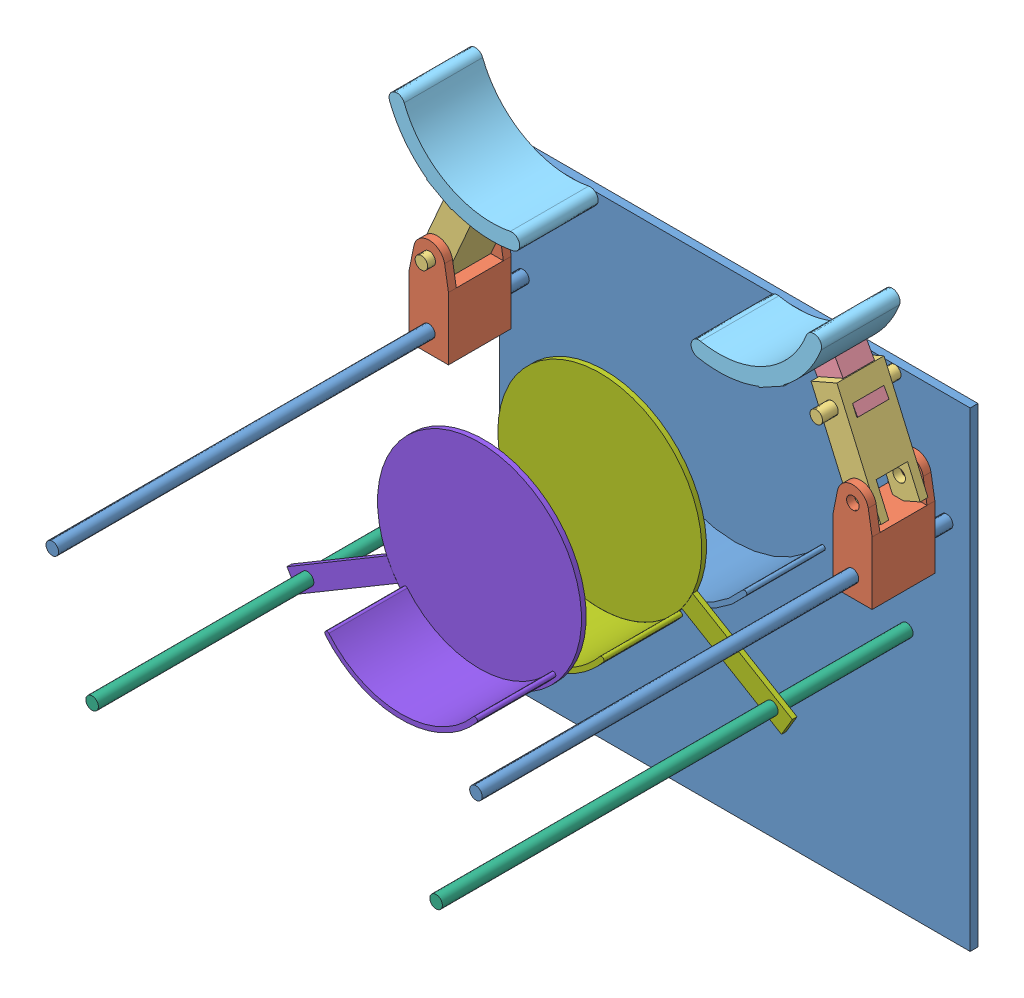
SolidWorks assembly ROBOT, configuration Défaut. Lengths in mm.
Overall size (300 375.39 305).
13 component instances, 8 part files, 17 mates.
Components (placement in the parent):
- Base-1: Base [Défaut] at (-204.6552 44.846 133.9619) size (300 300 305)
- Bras1-1: Bras1 [Défaut] at (-177.1552 -17.6611 178.9619) x (0 -1 0) z (-1 0 0) size (62.75 40 25)
- Bras1-2: Bras1 [Défaut] at (92.8448 -17.6611 178.9619) x (0 -1 0) z (-1 0 0) size (62.75 40 25)
- Bras2-1: Bras2 [Défaut] at (-194.5149 3.4054 178.9619) x (-0.916347 0.400384 0) z (0.400384 0.916347 0) size (18 50 70)
- Bras3-1: Bras3 [Défaut] at (-167.8613 62.6587 168.9619) x (0.481509 0.876441 0) z (0 0 1) size (30 18 30)
- Bras4-1: Bras4 [Défaut] at (-126.9093 137.1432 171.4619) x (-0.412255 -0.911069 0) z (0 0 1) size (29.08 93.31 50)
- Bras3-2: Bras3 [Défaut] at (58.5509 62.6587 188.9619) x (-0.481509 0.876441 0) z (0 0 -1) size (30 18 30)
- Bras2-2: Bras2 [Défaut] at (57.1777 67.5497 178.9619) x (0.916347 0.400384 0) z (0.400384 -0.916347 0) size (18 50 70)
- Bras4-2: Bras4 [Défaut] at (17.5989 137.1432 221.4619) x (0.412255 -0.911069 0) z (0 0 -1) size (29.08 93.31 50)
- Tige guidage-1: Tige guidage [Défaut] at (-164.2622 -97.8678 138.9619) size (8 8 300)
- Tige guidage-2: Tige guidage [Défaut] at (54.9518 -97.8678 438.9619) x (-1 0 0) z (0 0 -1) size (8 8 300)
- Plateau-2: Plateau [Défaut] at (-54.6552 -32.7778 221.98) x (-0.859817 0.510602 0) z (0 0 1) size (203.67 133 53)
- Plateau2-1: Plateau2 [Défaut] at (-54.6552 -32.7778 298.6726) x (0.859817 0.510602 0) z (0 0 1) size (203.67 130 53)
Mates (geometry in assembly coordinates):
- Coaxiale4: concentric anti-aligned: cylinder of Base-1 through (-189.6552 -25.154 438.9619) axis (0 0 -1) radius 4; cylinder of Bras1-1 through (-189.6552 -25.154 151.9619) axis (0 0 1) radius 4
- Parallèle2: parallel aligned: plane of Base-1 through (-204.6552 44.846 138.9619) normal (-1 0 0); plane of Bras1-1 through (-202.1552 -17.6611 178.9619) normal (-1 0 0)
- Coaxiale5: concentric anti-aligned: circle of Bras1-1; cylinder of Bras2-1 through (-189.41 15.0888 203.9619) axis (0 0 -1) radius 4
- Coïncidente7: coincident anti-aligned: plane of Bras1-1 through (-189.41 15.0888 193.9619) normal (0 0 -1); plane of Bras2-1 through (-158.2409 63.9463 193.9619) normal (0 0 1)
- Coaxiale6: concentric anti-aligned: cylinder of Bras2-1 through (-171.593 55.8663 151.9619) axis (0 0 1) radius 4; cylinder of Bras3-1 through (-171.593 55.8663 193.9619) axis (0 0 -1) radius 4
- Coïncidente8: coincident anti-aligned: plane of Bras2-1 through (-135.0928 32.0063 188.9619) normal (0 0 -1); plane of Bras3-1 through (-167.8613 62.6587 188.9619) normal (0 0 1)
- Coïncidente10: coincident anti-aligned: plane of Bras3-1 through (-168.5266 80.1389 188.9619) normal (0.481509 0.876441 0); plane of Bras4-1 through (-168.5266 80.1389 221.4619) normal (-0.481509 -0.876441 0)
- Coïncidente12: coincident aligned: line of Bras3-1 through (-168.5266 80.1389 188.9619) axis (0 0 -1); line of Bras4-1 through (-168.5266 80.1389 221.4619) axis (0 0 -1)
- Distance3: distance = 2.5 mm aligned: plane of Bras4-1 through (-187.5038 113.6207 171.4619) normal (0 0 -1); plane of Bras3-1 through (-167.8613 62.6587 168.9619) normal (0 0 -1)
- DistanceLimite2: limit distance = 240 mm aligned: plane of Bras1-1 through (-202.1552 2.3389 198.9619) normal (0 0 1); plane of Base-1 through (-189.6552 -25.154 438.9619) normal (0 0 1)
- Coïncidente13: coincident anti-aligned: plane of Base-1 through (-204.6552 44.846 138.9619) normal (0 0 1); plane of Tige guidage-1 through (-164.2622 -97.8678 138.9619) normal (0 0 -1)
- Verrouiller1: lock: unknown of Base-1; unknown of Tige guidage-1
- Coaxiale8: concentric aligned: cylinder of Tige guidage-2 through (54.9518 -97.8678 138.9619) axis (0 0 1) radius 4; cylinder of Plateau-2 through (54.9518 -97.8678 221.98) axis (0 0 1) radius 4
- Verrouiller2: lock: 
- Coaxiale10: concentric anti-aligned: cylinder of Tige guidage-1 through (-164.2622 -97.8678 438.9619) axis (0 0 -1) radius 4; cylinder of Plateau2-1 through (-164.2622 -97.8678 298.6726) axis (0 0 1) radius 4
- Coaxiale13: concentric aligned: circle of Base-1; circle of Plateau-2
- Coaxiale14: concentric anti-aligned: circle of Plateau-2; circle of Plateau2-1
